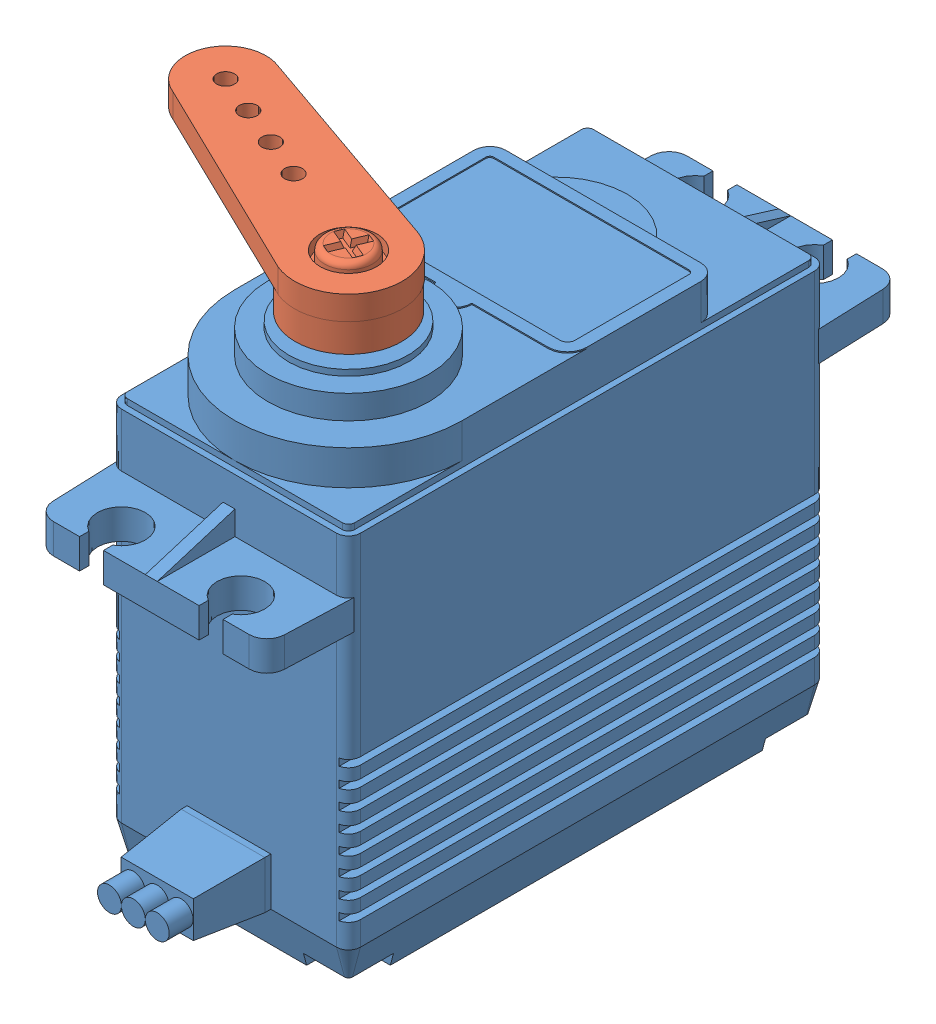
SolidWorks assembly Assembly, configuration Default. Lengths in mm.
Overall size (32.4 45 54.5).
2 component instances, 2 part files, 5 mates.
Components (placement in the parent):
- Hitec HS-7955TG-1: Hitec HS-7955TG [Default] at (-10 3.5 20) x (-1 0 0) z (0 0 -1) size (20 42.5 54.5)
- Hitec Servo Arm Alluminium-1: Hitec Servo Arm Alluminium [Default] at (-10 40.1 30) x (-0.923841 0 -0.382777) z (0.382777 0 -0.923841) size (26.88 4.9 9)
Mates (geometry in assembly coordinates):
- Concentric1: concentric anti-aligned: cylinder of Hitec HS-7955TG-1 through (-10 37.5 -25.2129) axis (0 1 0) radius 1.25; cylinder of Hitec Servo Arm Alluminium-1 through (-10 43.1 -25.2129) axis (0 -1 0) radius 2.905
- Distance1: distance = 44.5 mm anti-aligned: plane of Hitec Servo Arm Alluminium-1 through (-10 44.5 30) normal (0 1 0); plane of Hitec HS-7955TG-1 through (-1 0 39) normal (0 -1 0)
- Coincident5: coincident anti-aligned: plane of Hitec HS-7955TG-1 through (0 33.5 0) normal (0 0 -1); plane of assembly
- Coincident3: coincident aligned: plane of ? through (0 33.5 -15.2129) normal (1 0 0)
- Coincident4: coincident anti-aligned: plane of ? through (-1 0 -16.2129) normal (0 -1 0)
